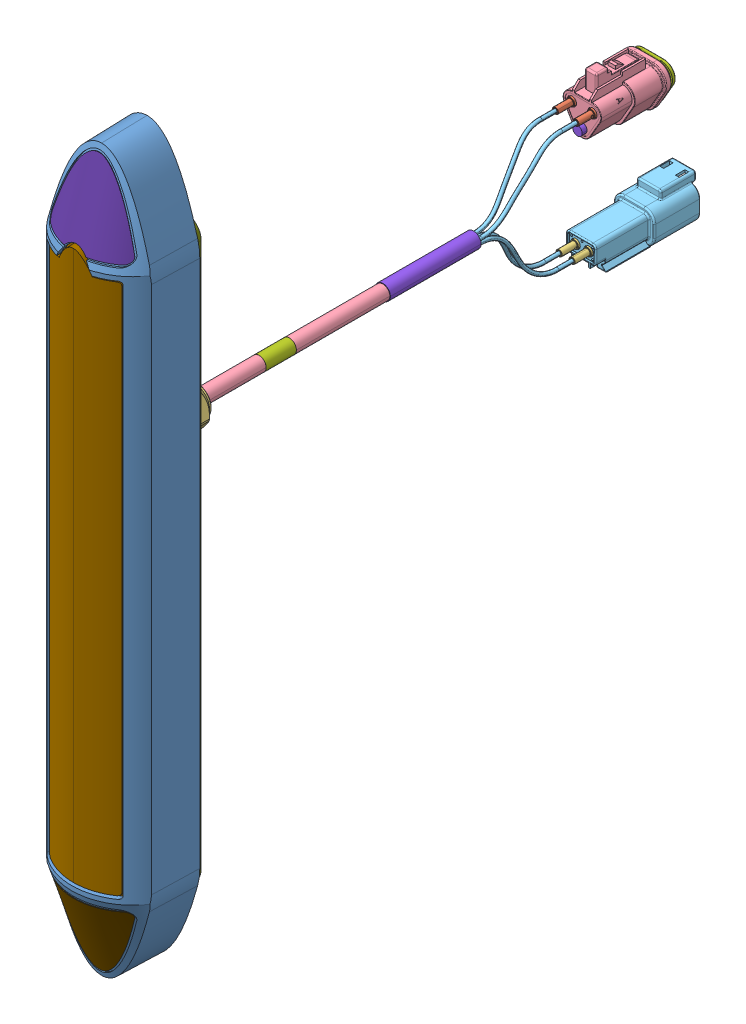
SolidWorks assembly 3050854-XX-XX-XX, configuration Default. Lengths in mm.
Overall size (44.25 303.73 257.37).
48 component instances, 26 part files, 0 mates.
Components (placement in the parent):
- 3030807-XX.STEP-1: 3030807-XX.STEP [Default] at origin size (39.47 279.52 206.75)
  - 4008399.STEP-1: 4008399.STEP [Default] at (0 38.1 0.0187) x (0.383049 -0.923728 0) z (0.923728 0.383049 0) size (18.09 29.47 17.97)
    - CG-30-BODY.STEP-1: CG-30-BODY.STEP [Default] at origin size (18.09 29.47 17.97)
      - CG-30-BODY-01^CG-30-BODY.STEP-1: CG-30-BODY-01^CG-30-BODY.STEP [Default] at origin size (18.09 26.87 17.83)
      - CG-30-BODY-02^CG-30-BODY.STEP-1: CG-30-BODY-02^CG-30-BODY.STEP [Default] at (0 11.3538 0) size (8.99 5.92 8.99)
      - CG-30-BODY-03^CG-30-BODY.STEP-1: CG-30-BODY-03^CG-30-BODY.STEP [Default] at (0 8.636 0) x (-1 0 0) z (0 0 -1) size (18.08 12.38 17.97)
  - 4090213.STEP-1: 4090213.STEP [Default] at (0 0 16.9271) size (14.49 52.78 191.07)
    - 4012116.STEP-1: 4012116.STEP [Default] at (0 38.1 -14.3078) x (-1 0 0) z (0 0 -1) size (5.92 5.92 127)
    - Z4090213-wire-01.STEP-1: Z4090213-wire-01.STEP [Default] at (-0.6852 35.1086 32.8264) x (0 0 -1) z (0.986064 -0.166366 0) size (51.37 26.07 4.4)
    - Z4090213-wire-01.STEP-2: Z4090213-wire-01.STEP [Default] at (2.275 35.1962 32.8264) x (0 0 -1) z (0.998374 -0.056998 0) size (51.37 26.07 4.4)
    - Z4090213-wire-01.STEP-3: Z4090213-wire-01.STEP [Default] at (1.1668 40.9466 32.8264) x (0 0 -1) z (-0.976592 0.215102 0) size (51.37 26.07 4.4)
    - Z4090213-wire-01.STEP-4: Z4090213-wire-01.STEP [Default] at (-2.0755 40.8374 32.8264) x (0 0 -1) z (-0.999749 -0.022408 0) size (51.37 26.07 4.4)
    - Z4090213-wire-02.STEP-1: Z4090213-wire-02.STEP [Default] at (0 38.1 -14.3078) size (3.3 3.3 12.7)
    - 4012020.STEP-1: 4012020.STEP [Default] at (0 38.1 -70.2956) x (0.697766 -0.716326 0) z (0 0 1) size (5.94 5.94 12.7)
    - 4012016.STEP-1: 4012016.STEP [Default] at (0 38.1 -134.9578) size (6.35 6.35 38.1)
  - 3100931.STEP-1: 3100931.STEP [Default] at (0 0 5.7943) size (39.47 279.52 25.84)
  - 3100933.STEP-1: 3100933.STEP [Default] at (0 0 0.0793) size (38.61 245.62 2.29)
  - 3100938.STEP-1: 3100938.STEP [Default] at (0 0 2.6193) size (39.14 246.15 3.19)
  - 3100773.STEP-1: 3100773.STEP [Default] at (0 0 5.7943) x (-1 0 0) z (0 0 -1) size (32.51 251.49 23.85)
  - 3002851.STEP-1: 3002851.STEP [Default] at (0 88.9 -0.1747) size (7.94 7.94 0.25)
  - 4051157.STEP-1: 4051157.STEP [Default] at (-16.256 111.125 7.077) x (0.91809 0.396373 0) z (0 0 -1) size (4.06 4.06 13.2)
  - 4051157.STEP-2: 4051157.STEP [Default] at (-16.256 66.675 7.077) x (0.84363 0.536925 0) z (0 0 -1) size (4.06 4.06 13.2)
  - 4051157.STEP-3: 4051157.STEP [Default] at (16.256 111.125 7.077) x (0.84363 0.536925 0) z (0 0 -1) size (4.06 4.06 13.2)
  - 4051157.STEP-4: 4051157.STEP [Default] at (16.256 66.675 7.077) x (0.768395 0.639975 0) z (0 0 -1) size (4.06 4.06 13.2)
  - 4051157.STEP-5: 4051157.STEP [Default] at (16.256 22.225 7.077) x (0.705397 0.708813 0) z (0 0 -1) size (4.06 4.06 13.2)
  - 4051157.STEP-6: 4051157.STEP [Default] at (-16.256 22.225 7.077) x (0.665764 0.746163 0) z (0 0 -1) size (4.06 4.06 13.2)
  - 4051157.STEP-7: 4051157.STEP [Default] at (16.256 -22.225 7.077) x (0.658474 0.752604 0) z (0 0 -1) size (4.06 4.06 13.2)
  - 4051157.STEP-8: 4051157.STEP [Default] at (-16.256 -22.225 7.077) x (0.688586 0.725155 0) z (0 0 -1) size (4.06 4.06 13.2)
  - 4051157.STEP-9: 4051157.STEP [Default] at (16.256 -66.675 7.077) x (0.753391 0.657573 0) z (0 0 -1) size (4.06 4.06 13.2)
  - 4051157.STEP-10: 4051157.STEP [Default] at (-16.256 -66.675 7.077) x (0.838159 0.545426 0) z (0 0 -1) size (4.06 4.06 13.2)
  - 4051157.STEP-11: 4051157.STEP [Default] at (16.256 -111.125 7.077) x (0.91809 0.396373 0) z (0 0 -1) size (4.06 4.06 13.2)
  - 4051157.STEP-12: 4051157.STEP [Default] at (-16.256 -111.125 7.077) x (0.971758 0.235981 0) z (0 0 -1) size (4.06 4.06 13.2)
  - 3102632.STEP-1: 3102632.STEP [Default] at (0 0 2.3653) size (38.61 245.62 0.25)
  - 3102632.STEP-2: 3102632.STEP [Default] at (0 0 -0.1747) size (38.61 245.62 0.25)
  - 3102640.STEP-1: 3102640.STEP [Default] at (0 0 -3.3497) size (38.61 245.62 3.17)
- 3101795-XX-XX-XX.STEP-1: 3101795-XX-XX-XX.STEP [Default] at (0 0 0.5588) size (35.84 297.46 11.2)
  - Z3101795-1.STEP-1: Z3101795-1.STEP [Default] at (0 0 0.5588) size (35.84 33.28 11.09)
  - Z3101795-2 .STEP-1: Z3101795-2 .STEP [Default] at (0 0 0.5588) x (-1 0 0) z (0 0 1) size (35.84 33.38 11.2)
- 3101772-XX.STEP-1: 3101772-XX.STEP [Default] at origin size (44.25 303.73 31.91)
- 4008093.STEP-1: 4008093.STEP [Default] at (4.3335 63.462 -194.5793) x (1 0 0) z (0 0 -1) size (3.3 3.3 18.81)
- 4008093.STEP-2: 4008093.STEP [Default] at (-4.3335 63.462 -194.5793) x (-0.752974 -0.658051 0) z (0 0 -1) size (3.3 3.3 18.81)
- 4008094.STEP-1: 4008094.STEP [Default] at (2.7305 12.4638 -196.3264) x (-0.102241 -0.99476 0) z (0 0 -1) size (3.35 4.84 20.57)
- 4008116.STEP-1: 4008116.STEP [Default] at (0 60.96 -211.0379) x (-1 0 0) z (0 0 -1) size (23.35 25.91 28.4)
- 4008081.STEP-1: 4008081.STEP [Default] at (0 11.4753 -223.6001) x (-1 0 0) z (0 0 -1) size (17.15 17.56 43.51)
- 4008095.STEP-1: 4008095.STEP [Default] at (-5.2215 7.3889 -205.6931) x (0 0 1) z (1 0 0) size (13.08 3.86 10.25)
- 4008117.STEP-1: 4008117.STEP [Default] at (0.1109 60.9194 -191.8889) x (-0.5 0.866025 0) z (0 0 1) size (20.98 18.17 20.83)
- 4008080.STEP-1: 4008080.STEP [Default] at (0 55.956 -180.7103) x (1 0 0) z (0 0 -1) size (3.96 3.96 14.61)
- 4008094.STEP-2: 4008094.STEP [Default] at (-2.7305 12.4638 -196.3264) x (0.931804 -0.362963 0) z (0 0 -1) size (3.35 4.84 20.57)
